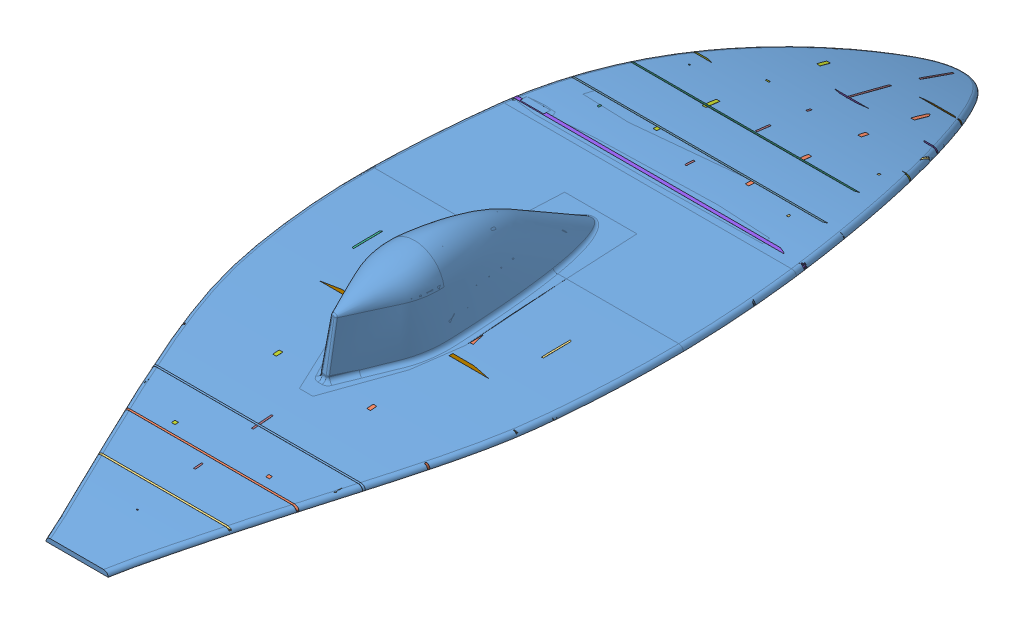
SolidWorks assembly Array Layout, configuration Default. Lengths in mm.
Overall size (2244.1 893.61 5149.59).
21 component instances, 21 part files, 64 mates.
Components (placement in the parent):
- Array Frame V2-1: Array Frame V2 [Default] at (1973.5044 2278.0681 4216.9276) size (2244.1 893.61 5149.59)
- Part2^Array Layout-1: Part2^Array Layout [Default] at (1973.5044 5406.8754 4216.9276) x (-1 0 0) z (0 -1 0) size (22.93 4512.12 270.66) (virtual)
- Part3^Array Layout-2: Part3^Array Layout [Default] at (0 5025.8754 0) x (-1 0 0) z (0 -1 0) size (12.76 3392.86 137.81) (virtual)
- Part4^Array Layout-1: Part4^Array Layout [Default] at (0 5025.8754 0) x (-1 0 0) z (0 -1 0) size (10.16 1424.94 59.48) (virtual)
- MirrorPart4^Array Layout-3: MirrorPart4^Array Layout [Default] at (6868.864 5025.8754 0) x (1 0 0) z (0 1 0) size (10.16 1424.94 59.48) (virtual)
- MirrorPart3^Array Layout-4: MirrorPart3^Array Layout [Default] at (6868.864 5025.8754 0) x (1 0 0) z (0 1 0) size (12.76 3392.86 137.81) (virtual)
- MirrorPart2^Array Layout-3: MirrorPart2^Array Layout [Default] at (4895.3596 5406.8754 4216.9276) x (1 0 0) z (0 1 0) size (22.93 4512.12 270.66) (virtual)
- Part9^Array Layout-1: Part9^Array Layout [Default] at (0 5025.8754 0) x (-1 0 0) z (0 -1 0) size (1654.54 20.33 77.9) (virtual)
- Part10^Array Layout-1: Part10^Array Layout [Default] at (0 5025.8754 0) x (-1 0 0) z (0 -1 0) size (1685.86 20.32 76.37) (virtual)
- Part11^Array Layout-1: Part11^Array Layout [Default] at (0 5025.8754 0) x (-1 0 0) z (0 -1 0) size (1724.27 10.17 52.31) (virtual)
- Part12^Array Layout-1: Part12^Array Layout [Default] at (0 5025.8754 0) x (-1 0 0) z (0 -1 0) size (1397.96 10.16 52.43) (virtual)
- Part5^Array Layout-1: Part5^Array Layout [Default] at (0 5025.8754 0) x (-1 0 0) z (0 -1 0) size (1623.76 20.32 66) (virtual)
- Part1^Array Layout-1: Part1^Array Layout [Default] at (0 5025.8754 0) x (-1 0 0) z (0 -1 0) size (10.55 4993.42 381) (virtual)
- Part6^Array Layout-1: Part6^Array Layout [Default] at (0 5025.8754 0) x (-1 0 0) z (0 -1 0) size (1553.22 10.16 52.29) (virtual)
- Part7^Array Layout-1: Part7^Array Layout [Default] at (0 5025.8754 0) x (-1 0 0) z (0 -1 0) size (1416.69 10.24 52.35) (virtual)
- Part8^Array Layout-1: Part8^Array Layout [Default] at (0 5025.8754 0) x (-1 0 0) z (0 -1 0) size (1239.18 10.16 52.42) (virtual)
- Part13^Array Layout-1: Part13^Array Layout [Default] at (0 5025.8754 0) x (-1 0 0) z (0 -1 0) size (1018.77 10.16 254.55) (virtual)
- Part14^Array Layout-1: Part14^Array Layout [Default] at origin size (734.38 52.67 10.16) (virtual)
- Part15^Array Layout-1: Part15^Array Layout [Default] at (0 5025.8754 0) x (-1 0 0) z (0 -1 0) size (1198 10.16 316.03) (virtual)
- Part16^Array Layout-1: Part16^Array Layout [Default] at (0 5025.8754 0) x (-1 0 0) z (0 -1 0) size (979.81 10.16 52.52) (virtual)
- Part17^Array Layout-1: Part17^Array Layout [Default] at (0 5025.8754 0) x (-1 0 0) z (0 -1 0) size (754.82 10.16 52.51) (virtual)
Mates (geometry in assembly coordinates):
- InPlace1: in place: plane of Array Frame V2-1 through (4331.3536 5406.8754 8301.6654) normal (0 -1 0); plane of ? through (0 5406.8754 0) normal (0 -1 0); moOrthogonalPlaneRef_w of Array Frame V2-1 through (4331.3536 5406.8754 8301.6654) normal (0 -1 0); plane of ? through (0 5406.8754 0) normal (0 0 -1); plane of Array Frame V2-1 through (4331.3536 5406.8754 8301.6654) normal (0 -1 0); plane of ? through (0 5406.8754 0) normal (-1 0 0); plane of Array Frame V2-1 through (4331.3536 5406.8754 8301.6654) normal (0 -1 0); unknown of Part2^Array Layout-1
- Coincident1: coincident aligned: plane of Array Frame V2-1; plane of Part2^Array Layout-1
- Coincident2: coincident aligned: moOrthogonalPlaneRef_w of Array Frame V2-1 through (1973.5044 5406.8754 4216.9276) normal (0 0 -1); plane of Part2^Array Layout-1 through (1973.5044 5406.8754 4216.9276) normal (0 0 -1)
- Coincident3: coincident anti-aligned: moOrthogonalPlaneRef_w of Array Frame V2-1 through (1973.5044 5406.8754 4216.9276) normal (1 0 0); plane of Part2^Array Layout-1 through (1973.5044 5406.8754 4216.9276) normal (-1 0 0)
- InPlace2: in place: plane of ? through (0 5025.8754 0) normal (0 -1 0); plane of ? through (0 5025.8754 0) normal (0 0 -1); plane of ? through (0 5025.8754 0) normal (-1 0 0); unknown of ?
- Coincident1: coincident aligned: 
- Coincident2: coincident aligned: plane of Part3^Array Layout-2 through (0 5025.8754 0) normal (0 0 -1)
- Coincident3: coincident anti-aligned: plane of Part3^Array Layout-2 through (0 5025.8754 0) normal (-1 0 0)
- InPlace3: in place: plane of ? through (0 5025.8754 0) normal (0 -1 0); plane of ? through (0 5025.8754 0) normal (0 0 -1); plane of ? through (0 5025.8754 0) normal (-1 0 0); unknown of ?
- Coincident4: coincident aligned: 
- Coincident5: coincident aligned: plane of Part4^Array Layout-1 through (0 5025.8754 0) normal (0 0 -1)
- Coincident6: coincident anti-aligned: plane of Part4^Array Layout-1 through (0 5025.8754 0) normal (-1 0 0)
- InPlace4: in place: plane of ? through (0 5025.8754 0) normal (0 -1 0); plane of ? through (0 5025.8754 0) normal (0 0 -1); plane of ? through (0 5025.8754 0) normal (-1 0 0); unknown of ?
- Coincident7: coincident aligned: 
- Coincident8: coincident aligned: plane of Part9^Array Layout-1 through (0 5025.8754 0) normal (0 0 -1)
- Coincident9: coincident anti-aligned: plane of Part9^Array Layout-1 through (0 5025.8754 0) normal (-1 0 0)
- InPlace5: in place: plane of ? through (0 5025.8754 0) normal (0 -1 0); plane of ? through (0 5025.8754 0) normal (0 0 -1); plane of ? through (0 5025.8754 0) normal (-1 0 0); unknown of ?
- Coincident10: coincident aligned: 
- Coincident11: coincident aligned: plane of Part10^Array Layout-1 through (0 5025.8754 0) normal (0 0 -1)
- Coincident12: coincident anti-aligned: plane of Part10^Array Layout-1 through (0 5025.8754 0) normal (-1 0 0)
- InPlace6: in place: plane of ? through (0 5025.8754 0) normal (0 -1 0); plane of ? through (0 5025.8754 0) normal (0 0 -1); plane of ? through (0 5025.8754 0) normal (-1 0 0); unknown of ?
- Coincident13: coincident aligned: 
- Coincident14: coincident aligned: plane of Part11^Array Layout-1 through (0 5025.8754 0) normal (0 0 -1)
- Coincident15: coincident anti-aligned: plane of Part11^Array Layout-1 through (0 5025.8754 0) normal (-1 0 0)
- InPlace7: in place: plane of ? through (0 5025.8754 0) normal (0 -1 0); plane of ? through (0 5025.8754 0) normal (0 0 -1); plane of ? through (0 5025.8754 0) normal (-1 0 0); unknown of ?
- Coincident16: coincident aligned: 
- Coincident17: coincident aligned: plane of Part12^Array Layout-1 through (0 5025.8754 0) normal (0 0 -1)
- Coincident18: coincident anti-aligned: plane of Part12^Array Layout-1 through (0 5025.8754 0) normal (-1 0 0)
- InPlace8: in place: plane of ? through (0 5025.8754 0) normal (0 -1 0); plane of ? through (0 5025.8754 0) normal (0 0 -1); plane of ? through (0 5025.8754 0) normal (-1 0 0); unknown of ?
- Coincident1: coincident aligned: 
- Coincident2: coincident aligned: plane of Part5^Array Layout-1 through (0 5025.8754 0) normal (0 0 -1)
- Coincident3: coincident anti-aligned: plane of Part5^Array Layout-1 through (0 5025.8754 0) normal (-1 0 0)
- InPlace9: in place: plane of ? through (0 5025.8754 0) normal (0 -1 0); plane of ? through (0 5025.8754 0) normal (0 0 -1); plane of ? through (0 5025.8754 0) normal (-1 0 0); unknown of ?
- Coincident1: coincident aligned: 
- Coincident2: coincident aligned: plane of Part1^Array Layout-1 through (0 5025.8754 0) normal (0 0 -1)
- Coincident3: coincident anti-aligned: plane of Part1^Array Layout-1 through (0 5025.8754 0) normal (-1 0 0)
- InPlace10: in place: plane of ? through (0 5025.8754 0) normal (0 -1 0); plane of ? through (0 5025.8754 0) normal (0 0 -1); plane of ? through (0 5025.8754 0) normal (-1 0 0); unknown of ?
- Coincident4: coincident aligned: 
- Coincident5: coincident aligned: plane of Part6^Array Layout-1 through (0 5025.8754 0) normal (0 0 -1)
- Coincident6: coincident anti-aligned: plane of Part6^Array Layout-1 through (0 5025.8754 0) normal (-1 0 0)
- InPlace11: in place: plane of ? through (0 5025.8754 0) normal (0 -1 0); plane of ? through (0 5025.8754 0) normal (0 0 -1); plane of ? through (0 5025.8754 0) normal (-1 0 0); unknown of ?
- Coincident7: coincident aligned: 
- Coincident8: coincident aligned: plane of Part7^Array Layout-1 through (0 5025.8754 0) normal (0 0 -1)
- Coincident9: coincident anti-aligned: plane of Part7^Array Layout-1 through (0 5025.8754 0) normal (-1 0 0)
- InPlace12: in place: plane of ? through (0 5025.8754 0) normal (0 -1 0); plane of ? through (0 5025.8754 0) normal (0 0 -1); plane of ? through (0 5025.8754 0) normal (-1 0 0); unknown of ?
- Coincident10: coincident aligned: 
- Coincident11: coincident aligned: plane of Part8^Array Layout-1 through (0 5025.8754 0) normal (0 0 -1)
- Coincident12: coincident anti-aligned: plane of Part8^Array Layout-1 through (0 5025.8754 0) normal (-1 0 0)
- InPlace13: in place: plane of ? through (0 5025.8754 0) normal (0 -1 0); plane of ? through (0 5025.8754 0) normal (0 0 -1); plane of ? through (0 5025.8754 0) normal (-1 0 0); unknown of ?
- Coincident13: coincident aligned: 
- Coincident14: coincident aligned: plane of Part13^Array Layout-1 through (0 5025.8754 0) normal (0 0 -1)
- Coincident15: coincident anti-aligned: plane of Part13^Array Layout-1 through (0 5025.8754 0) normal (-1 0 0)
- InPlace14: in place: plane of ? through (0 5025.8754 0) normal (0 -1 0); plane of ? through (0 5025.8754 0) normal (0 0 -1); plane of ? through (0 5025.8754 0) normal (-1 0 0); unknown of ?
- Coincident16: coincident aligned: 
- Coincident17: coincident aligned: plane of Part15^Array Layout-1 through (0 5025.8754 0) normal (0 0 -1)
- Coincident18: coincident anti-aligned: plane of Part15^Array Layout-1 through (0 5025.8754 0) normal (-1 0 0)
- InPlace15: in place: plane of ? through (0 5025.8754 0) normal (0 -1 0); plane of ? through (0 5025.8754 0) normal (0 0 -1); plane of ? through (0 5025.8754 0) normal (-1 0 0); unknown of ?
- Coincident1: coincident aligned: 
- Coincident2: coincident aligned: plane of Part16^Array Layout-1 through (0 5025.8754 0) normal (0 0 -1)
- Coincident3: coincident anti-aligned: plane of Part16^Array Layout-1 through (0 5025.8754 0) normal (-1 0 0)
- InPlace16: in place: plane of ? through (0 5025.8754 0) normal (0 -1 0); plane of ? through (0 5025.8754 0) normal (0 0 -1); plane of ? through (0 5025.8754 0) normal (-1 0 0); unknown of ?
- Coincident1: coincident aligned: plane of assembly through (0 5025.8754 0) normal (0 -1 0)
- Coincident2: coincident aligned: plane of Part17^Array Layout-1 through (0 5025.8754 0) normal (0 0 -1)
- Coincident3: coincident anti-aligned: plane of Part17^Array Layout-1 through (0 5025.8754 0) normal (-1 0 0)
